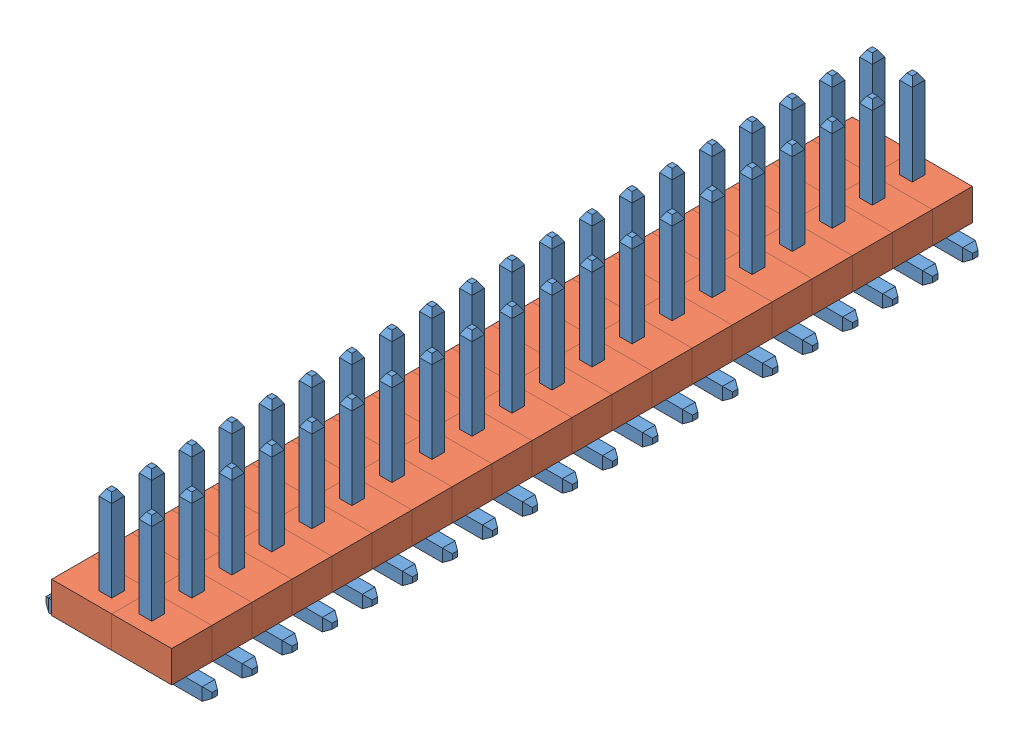
SolidWorks assembly Assem7, configuration Default. Lengths in mm.
Overall size (5.27 4.2 25.4).
120 component instances, 2 part files, 0 mates.
Components (placement in the parent):
- 1_27mm_single_pin_assembled-1: 1_27mm_single_pin_assembled [Default] at (0.1639 -0.4354 0.3241) size (2.64 4.2 1.27)
  - 1_27mm_pin_right_angle-1: 1_27mm_pin_right_angle [Default] at (-0.7701 -1.6572 -0.2335) size (2.2 4.2 0.4)
  - 1_27mm_plastic_for_pin-1: 1_27mm_plastic_for_pin [Default] at (-0.4526 -1.4572 -0.2335) x (0 0 -1) z (1 0 0) size (1.27 1 1.91)
- 1_27mm_single_pin_assembled-2: 1_27mm_single_pin_assembled [Default] at (0.1639 -0.4354 -0.9459) size (2.64 4.2 1.27)
  - 1_27mm_pin_right_angle-1: 1_27mm_pin_right_angle [Default] at (-0.7701 -1.6572 -0.2335) size (2.2 4.2 0.4)
  - 1_27mm_plastic_for_pin-1: 1_27mm_plastic_for_pin [Default] at (-0.4526 -1.4572 -0.2335) x (0 0 -1) z (1 0 0) size (1.27 1 1.91)
- 1_27mm_single_pin_assembled-3: 1_27mm_single_pin_assembled [Default] at (0.1639 -0.4354 -2.2159) size (2.64 4.2 1.27)
  - 1_27mm_pin_right_angle-1: 1_27mm_pin_right_angle [Default] at (-0.7701 -1.6572 -0.2335) size (2.2 4.2 0.4)
  - 1_27mm_plastic_for_pin-1: 1_27mm_plastic_for_pin [Default] at (-0.4526 -1.4572 -0.2335) x (0 0 -1) z (1 0 0) size (1.27 1 1.91)
- 1_27mm_single_pin_assembled-4: 1_27mm_single_pin_assembled [Default] at (0.1639 -0.4354 -3.4859) size (2.64 4.2 1.27)
  - 1_27mm_pin_right_angle-1: 1_27mm_pin_right_angle [Default] at (-0.7701 -1.6572 -0.2335) size (2.2 4.2 0.4)
  - 1_27mm_plastic_for_pin-1: 1_27mm_plastic_for_pin [Default] at (-0.4526 -1.4572 -0.2335) x (0 0 -1) z (1 0 0) size (1.27 1 1.91)
- 1_27mm_single_pin_assembled-5: 1_27mm_single_pin_assembled [Default] at (0.1639 -0.4354 -4.7559) size (2.64 4.2 1.27)
  - 1_27mm_pin_right_angle-1: 1_27mm_pin_right_angle [Default] at (-0.7701 -1.6572 -0.2335) size (2.2 4.2 0.4)
  - 1_27mm_plastic_for_pin-1: 1_27mm_plastic_for_pin [Default] at (-0.4526 -1.4572 -0.2335) x (0 0 -1) z (1 0 0) size (1.27 1 1.91)
- 1_27mm_single_pin_assembled-6: 1_27mm_single_pin_assembled [Default] at (0.1639 -0.4354 -6.0259) size (2.64 4.2 1.27)
  - 1_27mm_pin_right_angle-1: 1_27mm_pin_right_angle [Default] at (-0.7701 -1.6572 -0.2335) size (2.2 4.2 0.4)
  - 1_27mm_plastic_for_pin-1: 1_27mm_plastic_for_pin [Default] at (-0.4526 -1.4572 -0.2335) x (0 0 -1) z (1 0 0) size (1.27 1 1.91)
- 1_27mm_single_pin_assembled-7: 1_27mm_single_pin_assembled [Default] at (0.1639 -0.4354 -7.2959) size (2.64 4.2 1.27)
  - 1_27mm_pin_right_angle-1: 1_27mm_pin_right_angle [Default] at (-0.7701 -1.6572 -0.2335) size (2.2 4.2 0.4)
  - 1_27mm_plastic_for_pin-1: 1_27mm_plastic_for_pin [Default] at (-0.4526 -1.4572 -0.2335) x (0 0 -1) z (1 0 0) size (1.27 1 1.91)
- 1_27mm_single_pin_assembled-8: 1_27mm_single_pin_assembled [Default] at (0.1639 -0.4354 -8.5659) size (2.64 4.2 1.27)
  - 1_27mm_pin_right_angle-1: 1_27mm_pin_right_angle [Default] at (-0.7701 -1.6572 -0.2335) size (2.2 4.2 0.4)
  - 1_27mm_plastic_for_pin-1: 1_27mm_plastic_for_pin [Default] at (-0.4526 -1.4572 -0.2335) x (0 0 -1) z (1 0 0) size (1.27 1 1.91)
- 1_27mm_single_pin_assembled-9: 1_27mm_single_pin_assembled [Default] at (0.1639 -0.4354 -9.8359) size (2.64 4.2 1.27)
  - 1_27mm_pin_right_angle-1: 1_27mm_pin_right_angle [Default] at (-0.7701 -1.6572 -0.2335) size (2.2 4.2 0.4)
  - 1_27mm_plastic_for_pin-1: 1_27mm_plastic_for_pin [Default] at (-0.4526 -1.4572 -0.2335) x (0 0 -1) z (1 0 0) size (1.27 1 1.91)
- 1_27mm_single_pin_assembled-10: 1_27mm_single_pin_assembled [Default] at (0.1639 -0.4354 -11.1059) size (2.64 4.2 1.27)
  - 1_27mm_pin_right_angle-1: 1_27mm_pin_right_angle [Default] at (-0.7701 -1.6572 -0.2335) size (2.2 4.2 0.4)
  - 1_27mm_plastic_for_pin-1: 1_27mm_plastic_for_pin [Default] at (-0.4526 -1.4572 -0.2335) x (0 0 -1) z (1 0 0) size (1.27 1 1.91)
- 1_27mm_single_pin_assembled-11: 1_27mm_single_pin_assembled [Default] at (0.1639 -0.4354 -12.3759) size (2.64 4.2 1.27)
  - 1_27mm_pin_right_angle-1: 1_27mm_pin_right_angle [Default] at (-0.7701 -1.6572 -0.2335) size (2.2 4.2 0.4)
  - 1_27mm_plastic_for_pin-1: 1_27mm_plastic_for_pin [Default] at (-0.4526 -1.4572 -0.2335) x (0 0 -1) z (1 0 0) size (1.27 1 1.91)
- 1_27mm_single_pin_assembled-12: 1_27mm_single_pin_assembled [Default] at (0.1639 -0.4354 -13.6459) size (2.64 4.2 1.27)
  - 1_27mm_pin_right_angle-1: 1_27mm_pin_right_angle [Default] at (-0.7701 -1.6572 -0.2335) size (2.2 4.2 0.4)
  - 1_27mm_plastic_for_pin-1: 1_27mm_plastic_for_pin [Default] at (-0.4526 -1.4572 -0.2335) x (0 0 -1) z (1 0 0) size (1.27 1 1.91)
- 1_27mm_single_pin_assembled-13: 1_27mm_single_pin_assembled [Default] at (0.1639 -0.4354 -14.9159) size (2.64 4.2 1.27)
  - 1_27mm_pin_right_angle-1: 1_27mm_pin_right_angle [Default] at (-0.7701 -1.6572 -0.2335) size (2.2 4.2 0.4)
  - 1_27mm_plastic_for_pin-1: 1_27mm_plastic_for_pin [Default] at (-0.4526 -1.4572 -0.2335) x (0 0 -1) z (1 0 0) size (1.27 1 1.91)
- 1_27mm_single_pin_assembled-14: 1_27mm_single_pin_assembled [Default] at (0.1639 -0.4354 -16.1859) size (2.64 4.2 1.27)
  - 1_27mm_pin_right_angle-1: 1_27mm_pin_right_angle [Default] at (-0.7701 -1.6572 -0.2335) size (2.2 4.2 0.4)
  - 1_27mm_plastic_for_pin-1: 1_27mm_plastic_for_pin [Default] at (-0.4526 -1.4572 -0.2335) x (0 0 -1) z (1 0 0) size (1.27 1 1.91)
- 1_27mm_single_pin_assembled-15: 1_27mm_single_pin_assembled [Default] at (0.1639 -0.4354 -17.4559) size (2.64 4.2 1.27)
  - 1_27mm_pin_right_angle-1: 1_27mm_pin_right_angle [Default] at (-0.7701 -1.6572 -0.2335) size (2.2 4.2 0.4)
  - 1_27mm_plastic_for_pin-1: 1_27mm_plastic_for_pin [Default] at (-0.4526 -1.4572 -0.2335) x (0 0 -1) z (1 0 0) size (1.27 1 1.91)
- 1_27mm_single_pin_assembled-16: 1_27mm_single_pin_assembled [Default] at (0.1639 -0.4354 -18.7259) size (2.64 4.2 1.27)
  - 1_27mm_pin_right_angle-1: 1_27mm_pin_right_angle [Default] at (-0.7701 -1.6572 -0.2335) size (2.2 4.2 0.4)
  - 1_27mm_plastic_for_pin-1: 1_27mm_plastic_for_pin [Default] at (-0.4526 -1.4572 -0.2335) x (0 0 -1) z (1 0 0) size (1.27 1 1.91)
- 1_27mm_single_pin_assembled-17: 1_27mm_single_pin_assembled [Default] at (0.1639 -0.4354 -19.9959) size (2.64 4.2 1.27)
  - 1_27mm_pin_right_angle-1: 1_27mm_pin_right_angle [Default] at (-0.7701 -1.6572 -0.2335) size (2.2 4.2 0.4)
  - 1_27mm_plastic_for_pin-1: 1_27mm_plastic_for_pin [Default] at (-0.4526 -1.4572 -0.2335) x (0 0 -1) z (1 0 0) size (1.27 1 1.91)
- 1_27mm_single_pin_assembled-18: 1_27mm_single_pin_assembled [Default] at (0.1639 -0.4354 -21.2659) size (2.64 4.2 1.27)
  - 1_27mm_pin_right_angle-1: 1_27mm_pin_right_angle [Default] at (-0.7701 -1.6572 -0.2335) size (2.2 4.2 0.4)
  - 1_27mm_plastic_for_pin-1: 1_27mm_plastic_for_pin [Default] at (-0.4526 -1.4572 -0.2335) x (0 0 -1) z (1 0 0) size (1.27 1 1.91)
- 1_27mm_single_pin_assembled-19: 1_27mm_single_pin_assembled [Default] at (0.1639 -0.4354 -22.5359) size (2.64 4.2 1.27)
  - 1_27mm_pin_right_angle-1: 1_27mm_pin_right_angle [Default] at (-0.7701 -1.6572 -0.2335) size (2.2 4.2 0.4)
  - 1_27mm_plastic_for_pin-1: 1_27mm_plastic_for_pin [Default] at (-0.4526 -1.4572 -0.2335) x (0 0 -1) z (1 0 0) size (1.27 1 1.91)
- 1_27mm_single_pin_assembled-20: 1_27mm_single_pin_assembled [Default] at (0.1639 -0.4354 -23.8059) size (2.64 4.2 1.27)
  - 1_27mm_pin_right_angle-1: 1_27mm_pin_right_angle [Default] at (-0.7701 -1.6572 -0.2335) size (2.2 4.2 0.4)
  - 1_27mm_plastic_for_pin-1: 1_27mm_plastic_for_pin [Default] at (-0.4526 -1.4572 -0.2335) x (0 0 -1) z (1 0 0) size (1.27 1 1.91)
- 1_27mm_single_pin_assembled-21: 1_27mm_single_pin_assembled [Default] at (-2.6462 -0.4354 -16.653) x (-1 0 0) z (0 0 -1) size (2.64 4.2 1.27)
  - 1_27mm_pin_right_angle-1: 1_27mm_pin_right_angle [Default] at (-0.7701 -1.6572 -0.2335) size (2.2 4.2 0.4)
  - 1_27mm_plastic_for_pin-1: 1_27mm_plastic_for_pin [Default] at (-0.4526 -1.4572 -0.2335) x (0 0 -1) z (1 0 0) size (1.27 1 1.91)
- 1_27mm_single_pin_assembled-22: 1_27mm_single_pin_assembled [Default] at (-2.6462 -0.4354 -15.383) x (-1 0 0) z (0 0 -1) size (2.64 4.2 1.27)
  - 1_27mm_pin_right_angle-1: 1_27mm_pin_right_angle [Default] at (-0.7701 -1.6572 -0.2335) size (2.2 4.2 0.4)
  - 1_27mm_plastic_for_pin-1: 1_27mm_plastic_for_pin [Default] at (-0.4526 -1.4572 -0.2335) x (0 0 -1) z (1 0 0) size (1.27 1 1.91)
- 1_27mm_single_pin_assembled-23: 1_27mm_single_pin_assembled [Default] at (-2.6462 -0.4354 -11.573) x (-1 0 0) z (0 0 -1) size (2.64 4.2 1.27)
  - 1_27mm_pin_right_angle-1: 1_27mm_pin_right_angle [Default] at (-0.7701 -1.6572 -0.2335) size (2.2 4.2 0.4)
  - 1_27mm_plastic_for_pin-1: 1_27mm_plastic_for_pin [Default] at (-0.4526 -1.4572 -0.2335) x (0 0 -1) z (1 0 0) size (1.27 1 1.91)
- 1_27mm_single_pin_assembled-24: 1_27mm_single_pin_assembled [Default] at (-2.6462 -0.4354 -14.113) x (-1 0 0) z (0 0 -1) size (2.64 4.2 1.27)
  - 1_27mm_pin_right_angle-1: 1_27mm_pin_right_angle [Default] at (-0.7701 -1.6572 -0.2335) size (2.2 4.2 0.4)
  - 1_27mm_plastic_for_pin-1: 1_27mm_plastic_for_pin [Default] at (-0.4526 -1.4572 -0.2335) x (0 0 -1) z (1 0 0) size (1.27 1 1.91)
- 1_27mm_single_pin_assembled-25: 1_27mm_single_pin_assembled [Default] at (-2.6462 -0.4354 -10.303) x (-1 0 0) z (0 0 -1) size (2.64 4.2 1.27)
  - 1_27mm_pin_right_angle-1: 1_27mm_pin_right_angle [Default] at (-0.7701 -1.6572 -0.2335) size (2.2 4.2 0.4)
  - 1_27mm_plastic_for_pin-1: 1_27mm_plastic_for_pin [Default] at (-0.4526 -1.4572 -0.2335) x (0 0 -1) z (1 0 0) size (1.27 1 1.91)
- 1_27mm_single_pin_assembled-26: 1_27mm_single_pin_assembled [Default] at (-2.6462 -0.4354 -9.033) x (-1 0 0) z (0 0 -1) size (2.64 4.2 1.27)
  - 1_27mm_pin_right_angle-1: 1_27mm_pin_right_angle [Default] at (-0.7701 -1.6572 -0.2335) size (2.2 4.2 0.4)
  - 1_27mm_plastic_for_pin-1: 1_27mm_plastic_for_pin [Default] at (-0.4526 -1.4572 -0.2335) x (0 0 -1) z (1 0 0) size (1.27 1 1.91)
- 1_27mm_single_pin_assembled-27: 1_27mm_single_pin_assembled [Default] at (-2.6462 -0.4354 -12.843) x (-1 0 0) z (0 0 -1) size (2.64 4.2 1.27)
  - 1_27mm_pin_right_angle-1: 1_27mm_pin_right_angle [Default] at (-0.7701 -1.6572 -0.2335) size (2.2 4.2 0.4)
  - 1_27mm_plastic_for_pin-1: 1_27mm_plastic_for_pin [Default] at (-0.4526 -1.4572 -0.2335) x (0 0 -1) z (1 0 0) size (1.27 1 1.91)
- 1_27mm_single_pin_assembled-28: 1_27mm_single_pin_assembled [Default] at (-2.6462 -0.4354 -0.143) x (-1 0 0) z (0 0 -1) size (2.64 4.2 1.27)
  - 1_27mm_pin_right_angle-1: 1_27mm_pin_right_angle [Default] at (-0.7701 -1.6572 -0.2335) size (2.2 4.2 0.4)
  - 1_27mm_plastic_for_pin-1: 1_27mm_plastic_for_pin [Default] at (-0.4526 -1.4572 -0.2335) x (0 0 -1) z (1 0 0) size (1.27 1 1.91)
- 1_27mm_single_pin_assembled-29: 1_27mm_single_pin_assembled [Default] at (-2.6462 -0.4354 -1.413) x (-1 0 0) z (0 0 -1) size (2.64 4.2 1.27)
  - 1_27mm_pin_right_angle-1: 1_27mm_pin_right_angle [Default] at (-0.7701 -1.6572 -0.2335) size (2.2 4.2 0.4)
  - 1_27mm_plastic_for_pin-1: 1_27mm_plastic_for_pin [Default] at (-0.4526 -1.4572 -0.2335) x (0 0 -1) z (1 0 0) size (1.27 1 1.91)
- 1_27mm_single_pin_assembled-30: 1_27mm_single_pin_assembled [Default] at (-2.6462 -0.4354 -7.763) x (-1 0 0) z (0 0 -1) size (2.64 4.2 1.27)
  - 1_27mm_pin_right_angle-1: 1_27mm_pin_right_angle [Default] at (-0.7701 -1.6572 -0.2335) size (2.2 4.2 0.4)
  - 1_27mm_plastic_for_pin-1: 1_27mm_plastic_for_pin [Default] at (-0.4526 -1.4572 -0.2335) x (0 0 -1) z (1 0 0) size (1.27 1 1.91)
- 1_27mm_single_pin_assembled-31: 1_27mm_single_pin_assembled [Default] at (-2.6462 -0.4354 -6.493) x (-1 0 0) z (0 0 -1) size (2.64 4.2 1.27)
  - 1_27mm_pin_right_angle-1: 1_27mm_pin_right_angle [Default] at (-0.7701 -1.6572 -0.2335) size (2.2 4.2 0.4)
  - 1_27mm_plastic_for_pin-1: 1_27mm_plastic_for_pin [Default] at (-0.4526 -1.4572 -0.2335) x (0 0 -1) z (1 0 0) size (1.27 1 1.91)
- 1_27mm_single_pin_assembled-32: 1_27mm_single_pin_assembled [Default] at (-2.6462 -0.4354 -2.683) x (-1 0 0) z (0 0 -1) size (2.64 4.2 1.27)
  - 1_27mm_pin_right_angle-1: 1_27mm_pin_right_angle [Default] at (-0.7701 -1.6572 -0.2335) size (2.2 4.2 0.4)
  - 1_27mm_plastic_for_pin-1: 1_27mm_plastic_for_pin [Default] at (-0.4526 -1.4572 -0.2335) x (0 0 -1) z (1 0 0) size (1.27 1 1.91)
- 1_27mm_single_pin_assembled-33: 1_27mm_single_pin_assembled [Default] at (-2.6462 -0.4354 -5.223) x (-1 0 0) z (0 0 -1) size (2.64 4.2 1.27)
  - 1_27mm_pin_right_angle-1: 1_27mm_pin_right_angle [Default] at (-0.7701 -1.6572 -0.2335) size (2.2 4.2 0.4)
  - 1_27mm_plastic_for_pin-1: 1_27mm_plastic_for_pin [Default] at (-0.4526 -1.4572 -0.2335) x (0 0 -1) z (1 0 0) size (1.27 1 1.91)
- 1_27mm_single_pin_assembled-34: 1_27mm_single_pin_assembled [Default] at (-2.6462 -0.4354 -3.953) x (-1 0 0) z (0 0 -1) size (2.64 4.2 1.27)
  - 1_27mm_pin_right_angle-1: 1_27mm_pin_right_angle [Default] at (-0.7701 -1.6572 -0.2335) size (2.2 4.2 0.4)
  - 1_27mm_plastic_for_pin-1: 1_27mm_plastic_for_pin [Default] at (-0.4526 -1.4572 -0.2335) x (0 0 -1) z (1 0 0) size (1.27 1 1.91)
- 1_27mm_single_pin_assembled-35: 1_27mm_single_pin_assembled [Default] at (-2.6462 -0.4354 -21.733) x (-1 0 0) z (0 0 -1) size (2.64 4.2 1.27)
  - 1_27mm_pin_right_angle-1: 1_27mm_pin_right_angle [Default] at (-0.7701 -1.6572 -0.2335) size (2.2 4.2 0.4)
  - 1_27mm_plastic_for_pin-1: 1_27mm_plastic_for_pin [Default] at (-0.4526 -1.4572 -0.2335) x (0 0 -1) z (1 0 0) size (1.27 1 1.91)
- 1_27mm_single_pin_assembled-36: 1_27mm_single_pin_assembled [Default] at (-2.6462 -0.4354 -20.463) x (-1 0 0) z (0 0 -1) size (2.64 4.2 1.27)
  - 1_27mm_pin_right_angle-1: 1_27mm_pin_right_angle [Default] at (-0.7701 -1.6572 -0.2335) size (2.2 4.2 0.4)
  - 1_27mm_plastic_for_pin-1: 1_27mm_plastic_for_pin [Default] at (-0.4526 -1.4572 -0.2335) x (0 0 -1) z (1 0 0) size (1.27 1 1.91)
- 1_27mm_single_pin_assembled-37: 1_27mm_single_pin_assembled [Default] at (-2.6462 -0.4354 -19.193) x (-1 0 0) z (0 0 -1) size (2.64 4.2 1.27)
  - 1_27mm_pin_right_angle-1: 1_27mm_pin_right_angle [Default] at (-0.7701 -1.6572 -0.2335) size (2.2 4.2 0.4)
  - 1_27mm_plastic_for_pin-1: 1_27mm_plastic_for_pin [Default] at (-0.4526 -1.4572 -0.2335) x (0 0 -1) z (1 0 0) size (1.27 1 1.91)
- 1_27mm_single_pin_assembled-38: 1_27mm_single_pin_assembled [Default] at (-2.6462 -0.4354 -17.923) x (-1 0 0) z (0 0 -1) size (2.64 4.2 1.27)
  - 1_27mm_pin_right_angle-1: 1_27mm_pin_right_angle [Default] at (-0.7701 -1.6572 -0.2335) size (2.2 4.2 0.4)
  - 1_27mm_plastic_for_pin-1: 1_27mm_plastic_for_pin [Default] at (-0.4526 -1.4572 -0.2335) x (0 0 -1) z (1 0 0) size (1.27 1 1.91)
- 1_27mm_single_pin_assembled-39: 1_27mm_single_pin_assembled [Default] at (-2.6462 -0.4354 -23.003) x (-1 0 0) z (0 0 -1) size (2.64 4.2 1.27)
  - 1_27mm_pin_right_angle-1: 1_27mm_pin_right_angle [Default] at (-0.7701 -1.6572 -0.2335) size (2.2 4.2 0.4)
  - 1_27mm_plastic_for_pin-1: 1_27mm_plastic_for_pin [Default] at (-0.4526 -1.4572 -0.2335) x (0 0 -1) z (1 0 0) size (1.27 1 1.91)
- 1_27mm_single_pin_assembled-40: 1_27mm_single_pin_assembled [Default] at (-2.6462 -0.4354 -24.273) x (-1 0 0) z (0 0 -1) size (2.64 4.2 1.27)
  - 1_27mm_pin_right_angle-1: 1_27mm_pin_right_angle [Default] at (-0.7701 -1.6572 -0.2335) size (2.2 4.2 0.4)
  - 1_27mm_plastic_for_pin-1: 1_27mm_plastic_for_pin [Default] at (-0.4526 -1.4572 -0.2335) x (0 0 -1) z (1 0 0) size (1.27 1 1.91)
